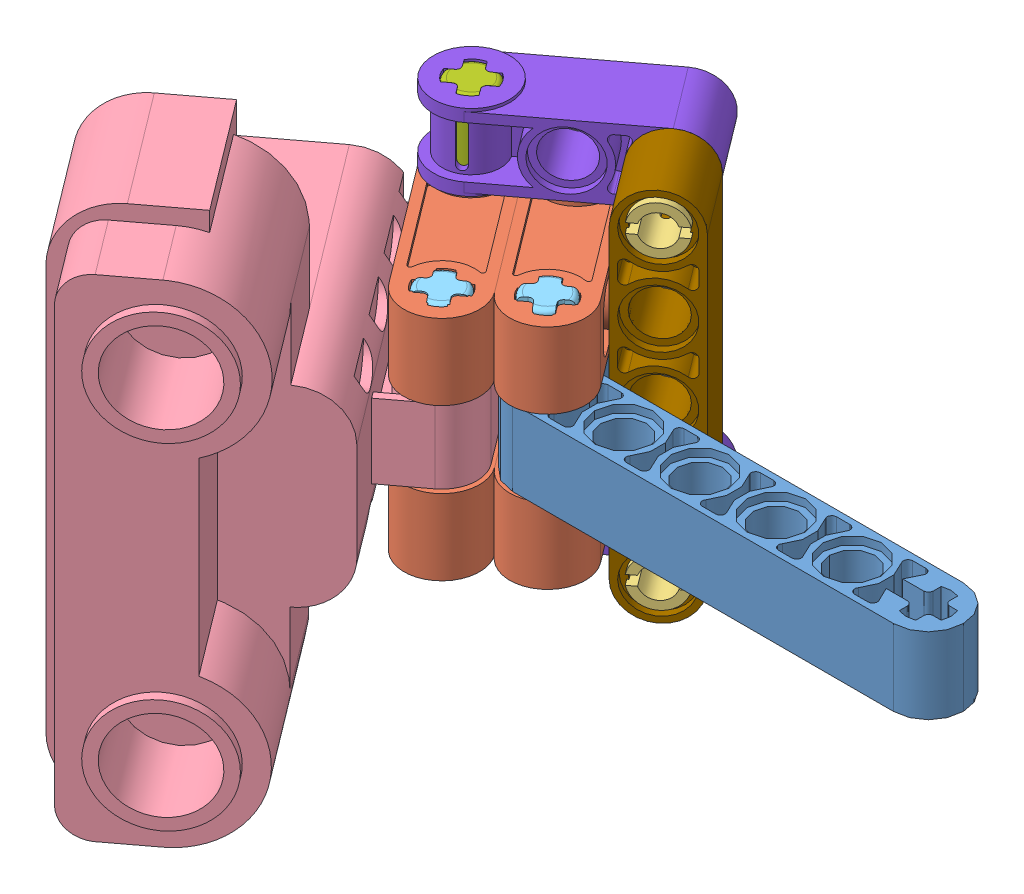
SolidWorks assembly Mantis step 19, configuration Default. Lengths in mm.
Overall size (84.72 55.29 62.72).
19 component instances, 9 part files, 15 mates.
Components (placement in the parent):
- Mantis step 18-1: Mantis step 18 [Default] at (18.955 -1.8596 0.0484) size (84.72 55.29 62.72)
  - beam_angle-1: beam_angle [Default] at (-9.7075 -7.1115 10.0876) size (62.29 8.06 26.73)
  - crossblock double-1: crossblock double [Predeterminado] at (-20.9111 4.9535 8.5131) x (0.601815 0 0.798636) z (0 1 0) size (24 8 8)
  - crossblock double-2: crossblock double [Predeterminado] at (-20.9111 -11.1115 8.5131) x (0.601815 0 0.798636) z (0 -1 0) size (24 8 8)
  - crossblock double-3: crossblock double [Predeterminado] at (-14.522 4.9535 3.6986) x (0.601815 0 0.798636) z (0 -1 0) size (24 8 8)
  - crossblock double-4: crossblock double [Predeterminado] at (-14.522 -11.1115 3.6986) x (0.601815 0 0.798636) z (0 1 0) size (24 8 8)
  - conn-1: conn [Default] at (-17.6766 4.9535 6.0757) x (0.601815 0 0.798636) z (0 -1 0) size (6.15 16.1 6.07)
  - conn-2: conn [Default] at (-17.6766 -11.1115 6.0757) x (0.601815 0 0.798636) z (0 1 0) size (6.15 16.1 6.07)
  - sensor_sonar-1: sensor_sonar [Default] at (-27.4904 -2.9715 25.5541) x (0 -1 0) z (0.798636 0 -0.601815) size (55.29 42.67 31.61)
  - axle_3-1: axle_3 [Default] at (-16.0965 -15.0908 14.9022) x (-0.793645 0 0.608381) z (-0.608381 0 -0.793645) size (4.78 24.27 4.78)
  - axle_3-2: axle_3 [Default] at (-9.7075 -14.8289 10.0876) x (0.789491 0 -0.613762) z (0.613762 0 0.789491) size (4.78 24.27 4.78)
  - axle_3-3: axle_3 [Default] at (-19.3365 -15.0105 -2.6905) x (0.794342 0 -0.607471) z (0.607471 0 0.794342) size (4.78 24.27 4.78)
  - socket-1: socket [Default] at (-39.3512 -2.9715 7.571) x (0 1 0) z (0.601815 0 0.798636) size (12.5 15 12.59)
- axle_5-1: axle_5 [Default] at (-6.7706 -25.1603 2.1724) x (-0.607839 0 -0.794061) z (0.794061 0 -0.607839) size (4.78 40.4 4.78)
- crossblock_3-3: crossblock_3 [Default] at (-0.5792 -21.0037 -2.4931) x (0.798636 0 -0.601815) z (0 1 0) size (23.57 8.06 8.06)
- crossblock_3-4: crossblock_3 [Default] at (-0.5792 11.1263 -2.4931) x (0.798636 0 -0.601815) z (0 1 0) size (23.57 8.06 8.06)
- beam_5-2: beam_5 [Default] at (8.2887 11.1263 -4.1263) x (0 -1 0) z (-0.798636 0 0.601815) size (39.7 8.06 7.44)
- conn-3: conn [Default] at (8.2887 11.1263 -4.1263) x (0.798636 0 -0.601815) z (0 -1 0) size (6.15 16.1 6.07)
- conn-4: conn [Default] at (8.2887 -21.1337 -4.1263) x (0.798636 0 -0.601815) z (0 -1 0) size (6.15 16.1 6.07)
Mates (geometry in assembly coordinates):
- Concentric1: concentric anti-aligned: circle of Mantis step 18-1/crossblock double-1; circle of crossblock_3-4
- Coincident1: coincident anti-aligned: plane of Mantis step 18-1/crossblock double-1 through (2.8585 7.0938 14.9506) normal (0 1 0); plane of crossblock_3-4 through (-0.8974 7.0938 2.9979) normal (0 -1 0)
- Parallel1: parallel aligned: plane of Mantis step 18-1/sensor_sonar-1 through (-8.6684 5.756 -1.2181) normal (-0.601815 0 -0.798636); plane of crossblock_3-4 through (-9.5095 14.9951 -0.8128) normal (-0.601815 0 -0.798636)
- Concentric2: concentric anti-aligned: circle of Mantis step 18-1/crossblock double-2; circle of crossblock_3-3
- Coincident3: coincident anti-aligned: plane of Mantis step 18-1/crossblock double-2 through (2.8585 -16.9712 14.9506) normal (0 -1 0); plane of crossblock_3-3 through (-7.596 -16.9712 8.0457) normal (0 1 0)
- Parallel2: parallel aligned: plane of crossblock_3-3 through (-9.5095 -17.1349 -0.8128) normal (-0.601815 0 -0.798636); plane of crossblock_3-4 through (-9.5095 14.9951 -0.8128) normal (-0.601815 0 -0.798636)
- Concentric3: concentric aligned: cylinder of axle_5-1 through (-6.7706 -24.6603 2.1724) axis (0 1 0) radius 2.39; cylinder of crossblock_3-4 through (-6.7706 7.0938 2.1724) axis (0 1 0) radius 2.39
- Lock1: lock: unknown of ?; unknown of ?
- Concentric4: concentric anti-aligned: cylinder of crossblock_3-4 through (7.7982 11.1263 -4.7772) axis (-0.601815 0 -0.798636) radius 2.39; cylinder of beam_5-2 through (8.7791 11.1263 -3.4754) axis (0.601815 0 0.798636) radius 2.39
- Coincident4: coincident anti-aligned: plane of crossblock_3-4 through (-4.6559 14.9951 5.6282) normal (0.601815 0 0.798636); plane of beam_5-2 through (5.1989 15.6465 -1.798) normal (-0.601815 0 -0.798636)
- Parallel5: parallel anti-aligned: plane of Mantis step 18-1/crossblock double-3 through (2.813 -0.9062 -5.0493) normal (0.798636 0 -0.601815); plane of beam_5-2 through (5.2207 11.7715 -2.0163) normal (-0.798636 0 0.601815)
- Coincident6: coincident aligned: circle of beam_5-2; circle of conn-4
- Coincident7: coincident aligned: circle of beam_5-2; circle of conn-3
- Parallel8: parallel anti-aligned: plane of conn-3 through (8.2887 11.1263 -4.1263) normal (0 -1 0); plane of assembly through (0 0 0) normal (0 1 0)
- Parallel9: parallel anti-aligned: plane of conn-4 through (8.2887 -21.1337 -4.1263) normal (0 -1 0); plane of assembly through (0 0 0) normal (0 1 0)
